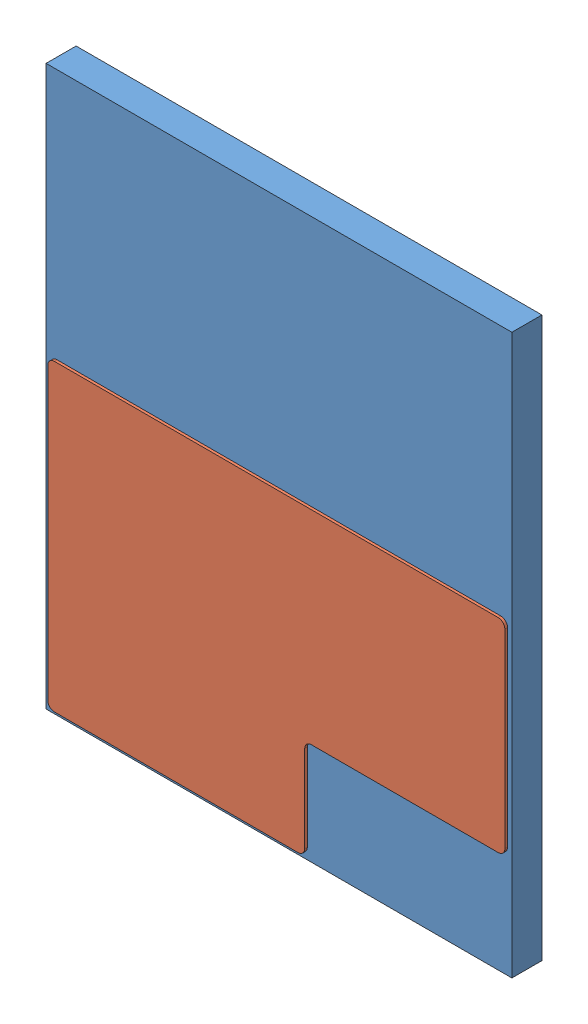
SolidWorks assembly GS66508B, configuration Default. Lengths in mm.
Overall size (6.98 8.38 0.49).
2 component instances, 2 part files, 0 mates.
Components (placement in the parent):
- Package-1: Package [Default] at (-0.2715 0.0344 6.2506) size (6.98 8.38 0.45)
- PCB Bottom CDMM-1: PCB Bottom CDMM [Default] at (-0.0115 0.0344 6.7006) size (6.85 4.55 0.04)
